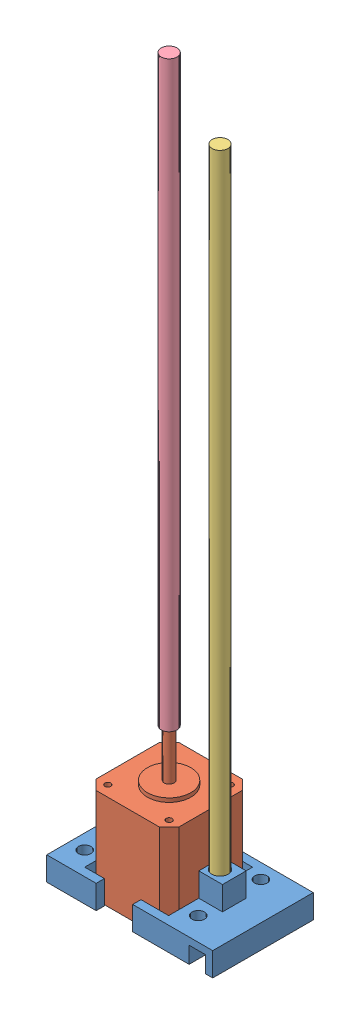
SolidWorks assembly _zAxisAssem, configuration Default. Lengths in mm.
Overall size (84 369 50.9).
4 component instances, 4 part files, 7 mates.
Components (placement in the parent):
- zMotorHolder-1: zMotorHolder [Default] at (-2.792 32.0901 103.9312) size (84 24 50.9)
- motor-1: motor [Default] at (-2.542 32.0901 103.4312) size (42 74 42)
- xyRods-1: xyRods [Default] at (44.458 44.0901 82.6812) x (-0.405772 0 0.913974) z (-0.913974 0 -0.405772) size (8 330 8)
- lead screw-1: lead screw [Default] at (18.458 106.0901 82.4312) x (0.306651 0 0.951822) z (-0.951822 0 0.306651) size (8 295 8)
Mates (geometry in assembly coordinates):
- Coincident1: coincident anti-aligned: plane of zMotorHolder-1 through (-2.792 44.0901 61.4312) normal (0 0 1); plane of motor-1 through (-2.792 80.0901 61.4312) normal (0 0 -1)
- Coincident3: coincident aligned: plane of zMotorHolder-1 through (-2.792 32.0901 103.9312) normal (0 -1 0); plane of motor-1 through (-2.792 32.0901 103.4312) normal (0 -1 0)
- Concentric1: concentric aligned: cylinder of zMotorHolder-1 through (44.458 56.0901 82.6812) axis (0 -1 0) radius 4.2; cylinder of xyRods-1 through (44.458 374.0901 82.6812) axis (0 -1 0) radius 4
- Coincident4: coincident anti-aligned: plane of zMotorHolder-1 through (-2.792 44.0901 103.9312) normal (0 1 0); plane of xyRods-1 through (44.458 44.0901 82.6812) normal (0 -1 0)
- Concentric2: concentric aligned: cylinder of motor-1 through (18.208 106.0901 82.4312) axis (0 -1 0) radius 2.5; cylinder of lead screw-1 through (18.208 401.0901 82.4312) axis (0 -1 0) radius 4
- Coincident5: coincident anti-aligned: plane of motor-1 through (18.208 106.0901 82.4312) normal (0 1 0); plane of lead screw-1 through (18.208 106.0901 82.4312) normal (0 -1 0)
- Width1: width anti-aligned: plane of motor-1 through (39.458 80.0901 103.4312) normal (1 0 0); plane of zMotorHolder-1 through (-2.542 80.0901 103.4312) normal (-1 0 0); plane of motor-1 through (39.708 44.0901 103.9312) normal (-1 0 0); plane of zMotorHolder-1 through (-2.792 44.0901 103.9312) normal (1 0 0)
